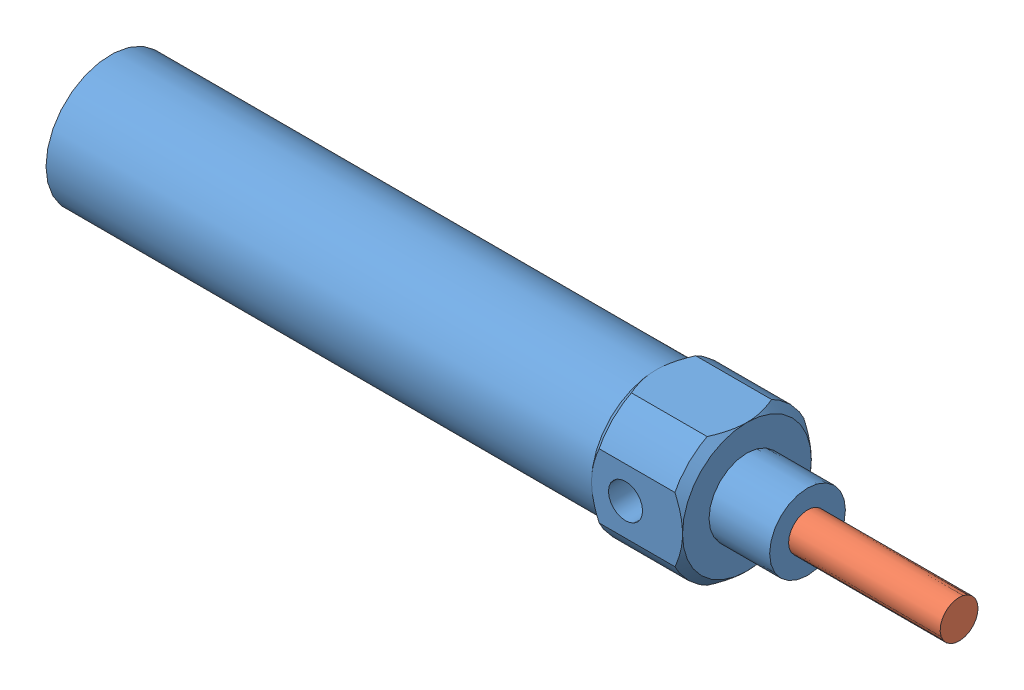
SolidWorks assembly エアシリンダ_可動40, configuration ﾃﾞﾌｫﾙﾄ. Lengths in mm.
Overall size (112 17 17).
2 component instances, 2 part files, 2 mates.
Components (placement in the parent):
- ボディ_40-1: ボディ_40 [ﾃﾞﾌｫﾙﾄ] at (-67.4414 2.0168 92) size (92 17 17)
- 軸_40-1: 軸_40 [ﾃﾞﾌｫﾙﾄ] at (-55.4414 2.0168 92) x (0 0.048832 -0.998807) z (1 0 0) size (6 6 100)
Mates (geometry in assembly coordinates):
- 同心円1: concentric anti-aligned: cylinder of ボディ_40-1 through (-55.4414 2.0168 92) axis (1 0 0) radius 2.5; cylinder of 軸_40-1 through (44.5586 2.0168 92) axis (-1 0 0) radius 2.5
- 距離制限1: limit distance = 20 mm aligned: plane of ボディ_40-1 through (24.5586 2.0168 92) normal (1 0 0); plane of 軸_40-1 through (44.5586 2.0168 92) normal (1 0 0)
